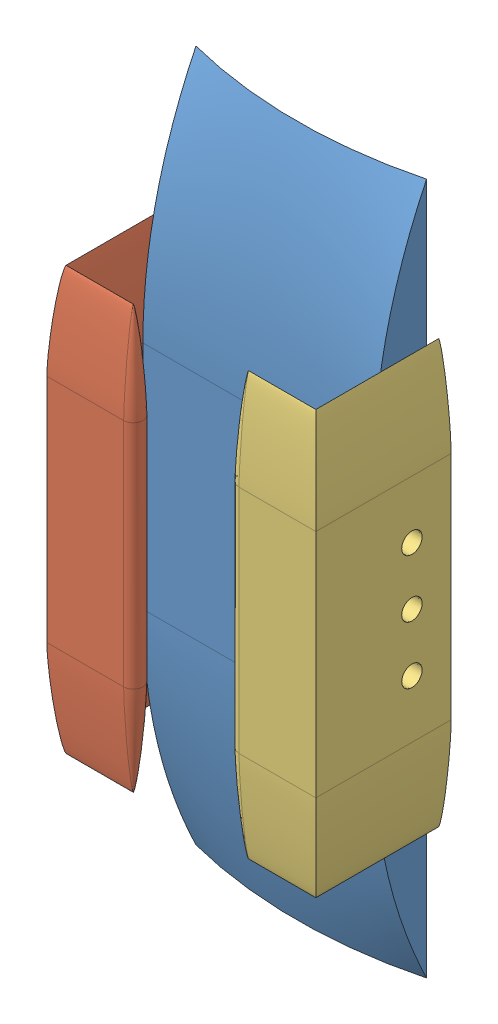
SolidWorks assembly 10007-R02_LAUNCH_LUG, configuration Default. Lengths in mm.
Overall size (90.78 228.6 46.28).
3 component instances, 3 part files, 9 mates.
Components (placement in the parent):
- 14031-R02_LAUNCH_LUG_FACE-2: 14031-R02_LAUNCH_LUG_FACE [Default] at origin size (76.36 228.6 22.35)
- 14040-R02_LAUNCH_LUG_LEFT-1: 14040-R02_LAUNCH_LUG_LEFT [Default] at origin size (29.52 139.7 46.08)
- 14039-R02_LAUNCH_LUG_RIGHT-2: 14039-R02_LAUNCH_LUG_RIGHT [Default] at origin size (29.52 139.7 46.08)
Mates (geometry in assembly coordinates):
- Coincident1: coincident: plane of 14031-R02_LAUNCH_LUG_FACE-2 through (0 0 0) normal (0 0 1); plane of assembly through (0 0 0) normal (0 0 1)
- Coincident3: coincident: plane of 14031-R02_LAUNCH_LUG_FACE-2 through (0 0 0) normal (0 1 0); plane of assembly through (0 0 0) normal (0 1 0)
- Coincident4: coincident: plane of 14031-R02_LAUNCH_LUG_FACE-2 through (0 0 0) normal (1 0 0); plane of assembly through (0 0 0) normal (1 0 0)
- Concentric1: concentric: circle of 14040-R02_LAUNCH_LUG_LEFT-1; circle of 14031-R02_LAUNCH_LUG_FACE-2
- Coincident6: coincident: plane of 14040-R02_LAUNCH_LUG_LEFT-1 through (-38.1 76.2 -17.5393) normal (1 0 0); plane of 14031-R02_LAUNCH_LUG_FACE-2 through (-38.1 76.2 0) normal (-1 0 0)
- Concentric2: concentric: circle of 14031-R02_LAUNCH_LUG_FACE-2; circle of 14039-R02_LAUNCH_LUG_RIGHT-2
- Coincident8: coincident: plane of 14031-R02_LAUNCH_LUG_FACE-2 through (38.1 76.2 0) normal (1 0 0); plane of 14039-R02_LAUNCH_LUG_RIGHT-2 through (38.1 72.4616 -22.2767) normal (-1 0 0)
- Concentric3: concentric: circle of 14031-R02_LAUNCH_LUG_FACE-2; circle of 14040-R02_LAUNCH_LUG_LEFT-1
- Concentric4: concentric: circle of 14031-R02_LAUNCH_LUG_FACE-2; circle of 14039-R02_LAUNCH_LUG_RIGHT-2
